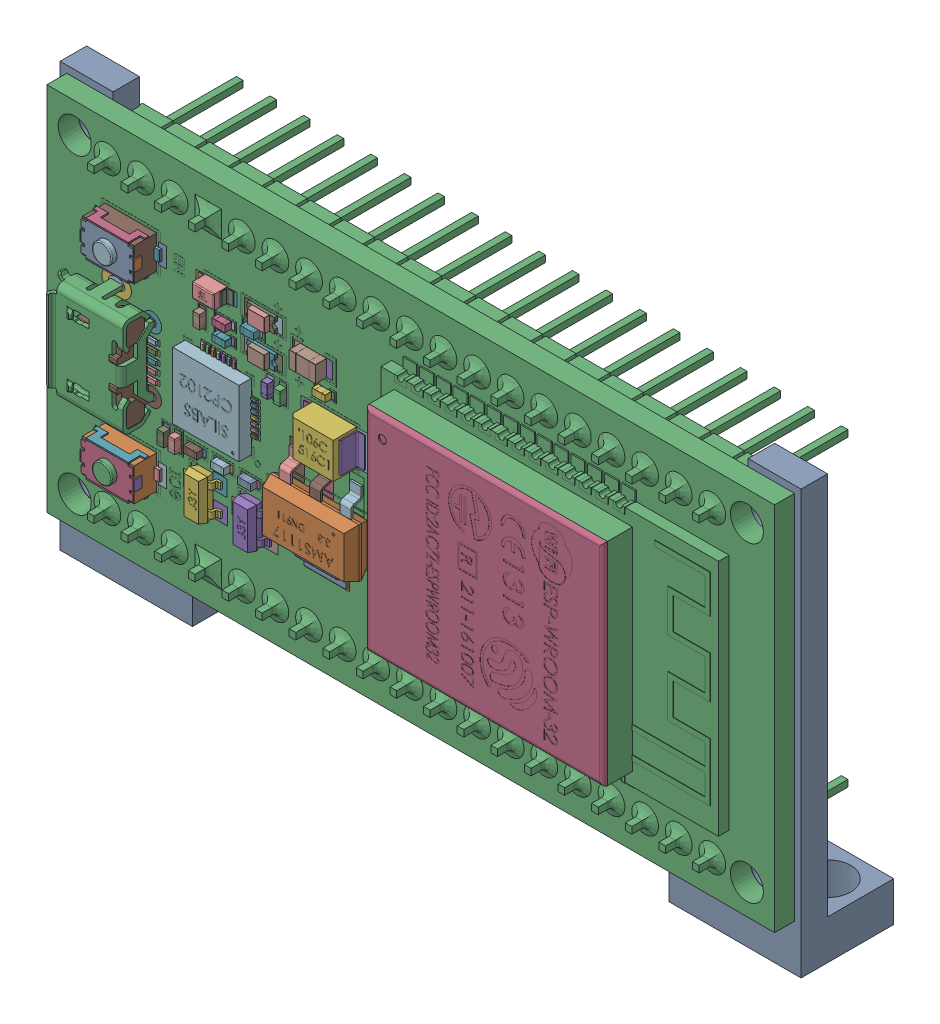
SolidWorks assembly support_esp32 + esp32, configuration Valor predeterminado. Lengths in mm.
Overall size (56 32 13).
2 component instances, 2 part files, 2 mates.
Components (placement in the parent):
- support_esp32-1: support_esp32 [Valor predeterminado] at (-6.0512 -0.7328 49.75) size (56 32 7)
- components_esp23_wroom_32s-1: components_esp23_wroom_32s [Default] at (130.9546 916.8965 -421.8016) x (1 0 0) z (0 -1 0) size (55 13 28)
Mates (geometry in assembly coordinates):
- Coincidente1: coincident anti-aligned: plane of suporte3 esp32-1 through (-6.0512 -0.7328 51.75) normal (0 0 1); plane of ESP32_Wroom_32S-1 through (7.9831 1.852 51.75) normal (0 0 -1)
- Concêntrico1: concentric anti-aligned: cylinder of suporte3 esp32-1 through (33.3831 13.6348 51.75) axis (0 0 -1) radius 1.25; cylinder of ESP32_Wroom_32S-1 through (33.3831 13.6348 49.88) axis (0 0 1) radius 1.25
